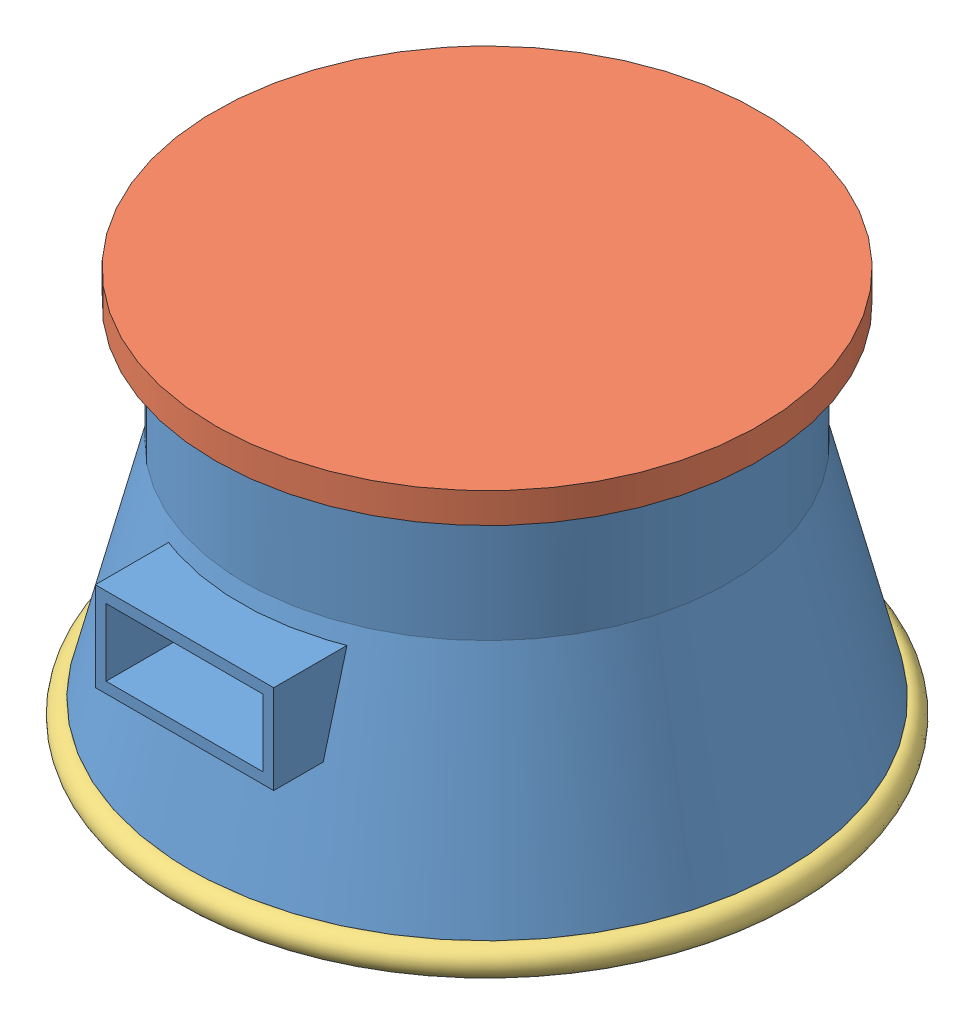
SolidWorks assembly EasyCardio_Assembly, configuration Default. Lengths in mm.
Overall size (63.55 33.15 63.55).
4 component instances, 3 part files, 4 mates.
Components (placement in the parent):
- Assem1^EasyCardio_Assembly-1: Assem1^EasyCardio_Assembly [Default] at (-13.967 -122.2278 -81.1905) size (50 30 50) (virtual)
  - EasyCardio main-1: EasyCardio main [Default] at (18.147 13.2617 37.1783) size (50 30 50)
- EasyCardio lid-1: EasyCardio lid [Default] at (4.1801 -83.966 -44.0122) x (-0.669693 0 0.742638) z (-0.742638 0 -0.669693) size (45 7.5 45)
- anti chill ring-1: anti chill ring [Default] at (4.1801 -108.966 -44.0122) x (0.99793 0 0.064314) z (-0.064314 0 0.99793) size (51.52 2.4 51.52)
Mates (geometry in assembly coordinates):
- Concentric6: concentric anti-aligned: cylinder of Assem1^EasyCardio-1/EasyCardio main-1 through (4.1801 -101.466 -44.0122) axis (0 1 0) radius 17.5; cylinder of EasyCardio lid-1 through (4.1801 -78.966 -44.0122) axis (0 -1 0) radius 17.5
- LimitDistance2: limit distance = 0 mm anti-aligned: plane of EasyCardio lid-1 through (4.1801 -78.966 -44.0122) normal (0 -1 0); plane of Assem1^EasyCardio-1/EasyCardio main-1 through (4.1801 -78.966 -44.0122) normal (0 1 0)
- Concentric8: concentric anti-aligned: cylinder of Assem1^EasyCardio-1/EasyCardio main-1 through (4.1801 -77.5045 -44.0122) axis (0 1 0) radius 23.75; cylinder of anti chill ring-1 through (4.1801 -108.966 -44.0122) axis (0 -1 0) radius 23.75
- Coincident10: coincident anti-aligned: plane of Assem1^EasyCardio-1/EasyCardio main-1 through (4.1801 -108.216 -44.0122) normal (0 -1 0); plane of anti chill ring-1 through (-19.7702 -108.216 -45.5557) normal (0 1 0)
